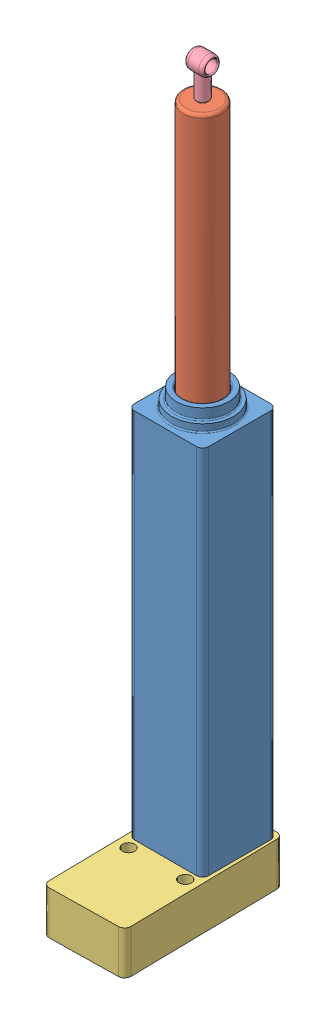
SolidWorks assembly assemblageVerin, configuration Défaut. Lengths in mm.
Overall size (134.45 1180.45 262.2).
4 component instances, 4 part files, 6 mates.
Components (placement in the parent):
- BaseVerin-1: BaseVerin [Défaut] at (-78.391 -108.5334 268) size (120 679 120)
- Verin-1: Verin [Défaut] at (-78.391 292.5867 268) x (-0.924202 0 0.381903) z (-0.381903 0 -0.924202) size (70 662 70)
- supportMoteur-1: supportMoteur [Défaut] at (-77.2727 -178.5334 332.9904) x (0.017204 0 0.999852) z (-0.999852 0 0.017204) size (260 70 130)
- attacheVerin-1: attacheVerin [Défaut] at (-78.391 924.5867 268) x (0.999999 0 -0.001089) z (0.001089 0 0.999999) size (40 77.33 40)
Mates (geometry in assembly coordinates):
- Coaxiale2: concentric: cylinder of BaseVerin-1 through (-78.391 491.4666 268) axis (0 1 0) radius 32.5; cylinder of Verin-1 through (-78.391 922.5867 268) axis (0 -1 0) radius 31.5
- Coaxiale4: concentric: cylinder of BaseVerin-1 through (-78.391 -158.5334 268) axis (0 1 0) radius 12.5; cylinder of supportMoteur-1 through (-78.391 -158.5334 268) axis (0 1 0) radius 12.5
- Coïncidente4: coincident: plane of BaseVerin-1 through (-78.391 -120.5334 268) normal (0 -1 0); plane of supportMoteur-1 through (-78.391 -120.5334 268) normal (0 1 0)
- Coaxiale5: concentric: cylinder of Verin-1 through (-78.391 954.5867 268) axis (0 -1 0) radius 7.25; cylinder of attacheVerin-1 through (-78.391 954.5867 268) axis (0 -1 0) radius 7.25
- Coïncidente6: coincident: circle of Verin-1; circle of attacheVerin-1
- Largeur1: width: plane of BaseVerin-1 through (-78.391 -98.5334 268) normal (0 1 0); plane of BaseVerin-1 through (-78.391 491.4666 268) normal (0 -1 0); plane of Verin-1 through (-78.391 292.5867 268) normal (0 -1 0); plane of Verin-1 through (-78.391 302.5867 268) normal (0 1 0)
